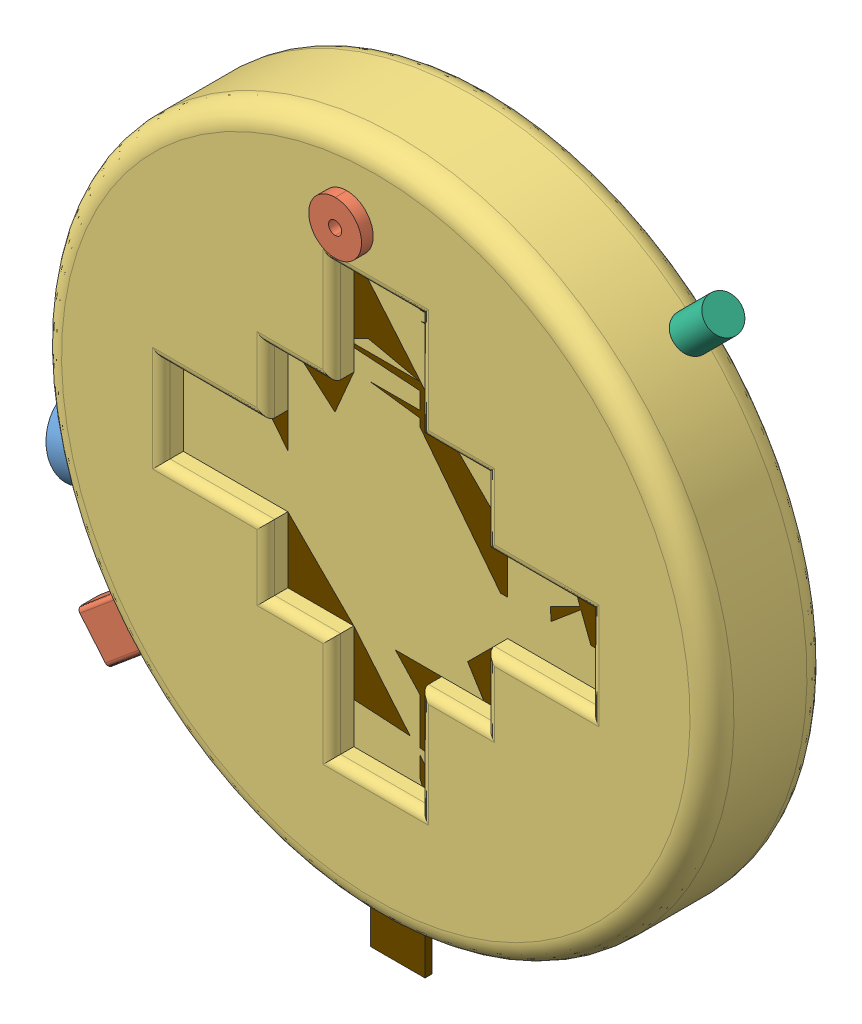
SolidWorks assembly Semafor2_s_obalem, configuration Výchozí. Lengths in mm.
Overall size (156.29 162.78 29.25).
175 component instances, 21 part files, 3 mates.
Components (placement in the parent):
- Semafor2_kompletni-1: Semafor2_kompletni [Výchozí] at origin size (154.19 160.68 28.8)
  - Semafor2-1: Semafor2 [Výchozí] at origin size (148.79 160.68 28.8)
    - Semafor2.step-1: Semafor2.step [Výchozí] at origin size (148.79 160.68 28.8)
      - LED_WS2812B_PLCC4_5.0x5.0mm_P3.2mm.step-1: LED_WS2812B_PLCC4_5.0x5.0mm_P3.2mm.step [Výchozí] at (-39.4282 65.1 1.65) x (0.5 0.866025 0) z (0 0 1) size (5.4 5 1.6)
        - SOLID.step-1: SOLID.step [Výchozí] at origin size (5.4 5 1.6)
      - Piezo.step-1: Piezo.step [Výchozí] at (-106.6 158.895 1.65) x (1 0 0) z (0 -1 0) size (12 7.6 12)
        - SOLID-0.step-1: SOLID-0.step [Výchozí] at origin size (12 7.6 12)
      - LED_WS2812B_PLCC4_5.0x5.0mm_P3.2mm.step-2: LED_WS2812B_PLCC4_5.0x5.0mm_P3.2mm.step [Výchozí] at (-30.05 100.1 1.65) x (0 1 0) z (0 0 1) size (5.4 5 1.6)
        - SOLID.step-1: SOLID.step [Výchozí] at origin size (5.4 5 1.6)
      - LED_WS2812B_PLCC4_5.0x5.0mm_P3.2mm.step-3: LED_WS2812B_PLCC4_5.0x5.0mm_P3.2mm.step [Výchozí] at (-170.05 100.1 1.65) x (0 -1 0) z (0 0 1) size (5.4 5 1.6)
        - SOLID.step-1: SOLID.step [Výchozí] at origin size (5.4 5 1.6)
      - C_0603_1608Metric.step-1: C_0603_1608Metric.step [Výchozí] at (-101.75 33.8 1.65) size (1.6 0.8 0.8)
        - SOLID-1.step-1: SOLID-1.step [Výchozí] at origin size (1.6 0.8 0.8)
      - C_0603_1608Metric.step-2: C_0603_1608Metric.step [Výchozí] at (-43.5875 65.6288 1.65) x (0.5 0.866025 0) z (0 0 1) size (1.6 0.8 0.8)
        - SOLID-1.step-1: SOLID-1.step [Výchozí] at origin size (1.6 0.8 0.8)
      - C_0603_1608Metric.step-3: C_0603_1608Metric.step [Výchozí] at (-134.4288 43.6125 1.65) x (0.866025 -0.5 0) z (0 0 1) size (1.6 0.8 0.8)
        - SOLID-1.step-1: SOLID-1.step [Výchozí] at origin size (1.6 0.8 0.8)
      - C_0603_1608Metric.step-4: C_0603_1608Metric.step [Výchozí] at (-166.15 101.75 1.65) x (0 -1 0) z (0 0 1) size (1.6 0.8 0.8)
        - SOLID-1.step-1: SOLID-1.step [Výchozí] at origin size (1.6 0.8 0.8)
      - LED_WS2812B_PLCC4_5.0x5.0mm_P3.2mm.step-4: LED_WS2812B_PLCC4_5.0x5.0mm_P3.2mm.step [Výchozí] at (-100.05 30.1 1.65) size (5.4 5 1.6)
        - SOLID.step-1: SOLID.step [Výchozí] at origin size (5.4 5 1.6)
      - C_0603_1608Metric.step-5: C_0603_1608Metric.step [Výchozí] at (-158.05 68.5 1.65) x (0.5 -0.866025 0) z (0 0 1) size (1.6 0.8 0.8)
        - SOLID-1.step-1: SOLID-1.step [Výchozí] at origin size (1.6 0.8 0.8)
      - C_0603_1608Metric.step-6: C_0603_1608Metric.step [Výchozí] at (-68.35 41.95 1.65) x (0.866025 0.5 0) z (0 0 1) size (1.6 0.8 0.8)
        - SOLID-1.step-1: SOLID-1.step [Výchozí] at origin size (1.6 0.8 0.8)
      - LED_WS2812B_PLCC4_5.0x5.0mm_P3.2mm.step-5: LED_WS2812B_PLCC4_5.0x5.0mm_P3.2mm.step [Výchozí] at (-100.05 170.1 1.65) x (-1 0 0) z (0 0 1) size (5.4 5 1.6)
        - SOLID.step-1: SOLID.step [Výchozí] at origin size (5.4 5 1.6)
      - LED_WS2812B_PLCC4_5.0x5.0mm_P3.2mm.step-6: LED_WS2812B_PLCC4_5.0x5.0mm_P3.2mm.step [Výchozí] at (-39.4282 135.1 1.65) x (-0.5 0.866025 0) z (0 0 1) size (5.4 5 1.6)
        - SOLID.step-1: SOLID.step [Výchozí] at origin size (5.4 5 1.6)
      - LED_WS2812B_PLCC4_5.0x5.0mm_P3.2mm.step-7: LED_WS2812B_PLCC4_5.0x5.0mm_P3.2mm.step [Výchozí] at (-160.6718 65.1 1.65) x (0.5 -0.866025 0) z (0 0 1) size (5.4 5 1.6)
        - SOLID.step-1: SOLID.step [Výchozí] at origin size (5.4 5 1.6)
      - LED_WS2812B_PLCC4_5.0x5.0mm_P3.2mm.step-8: LED_WS2812B_PLCC4_5.0x5.0mm_P3.2mm.step [Výchozí] at (-65.05 39.4782 1.65) x (0.866025 0.5 0) z (0 0 1) size (5.4 5 1.6)
        - SOLID.step-1: SOLID.step [Výchozí] at origin size (5.4 5 1.6)
      - C_0603_1608Metric.step-7: C_0603_1608Metric.step [Výchozí] at (-65.45 156.55 1.65) x (-0.866025 0.5 0) z (0 0 1) size (1.6 0.8 0.8)
        - SOLID-1.step-1: SOLID-1.step [Výchozí] at origin size (1.6 0.8 0.8)
      - C_0603_1608Metric.step-8: C_0603_1608Metric.step [Výchozí] at (-33.9 98.45 1.65) x (0 1 0) z (0 0 1) size (1.6 0.8 0.8)
        - SOLID-1.step-1: SOLID-1.step [Výchozí] at origin size (1.6 0.8 0.8)
      - C_0603_1608Metric.step-9: C_0603_1608Metric.step [Výchozí] at (-98.4 166.3 1.65) x (-1 0 0) z (0 0 1) size (1.6 0.8 0.8)
        - SOLID-1.step-1: SOLID-1.step [Výchozí] at origin size (1.6 0.8 0.8)
      - LED_WS2812B_PLCC4_5.0x5.0mm_P3.2mm.step-9: LED_WS2812B_PLCC4_5.0x5.0mm_P3.2mm.step [Výchozí] at (-160.6718 135.1 1.65) x (-0.5 -0.866025 0) z (0 0 1) size (5.4 5 1.6)
        - SOLID.step-1: SOLID.step [Výchozí] at origin size (5.4 5 1.6)
      - LED_WS2812B_PLCC4_5.0x5.0mm_P3.2mm.step-10: LED_WS2812B_PLCC4_5.0x5.0mm_P3.2mm.step [Výchozí] at (-65.05 160.7218 1.65) x (-0.866025 0.5 0) z (0 0 1) size (5.4 5 1.6)
        - SOLID.step-1: SOLID.step [Výchozí] at origin size (5.4 5 1.6)
      - C_0603_1608Metric.step-10: C_0603_1608Metric.step [Výchozí] at (-156.35 134.6 1.65) x (-0.5 -0.866025 0) z (0 0 1) size (1.6 0.8 0.8)
        - SOLID-1.step-1: SOLID-1.step [Výchozí] at origin size (1.6 0.8 0.8)
      - LED_WS2812B_PLCC4_5.0x5.0mm_P3.2mm.step-11: LED_WS2812B_PLCC4_5.0x5.0mm_P3.2mm.step [Výchozí] at (-135.05 160.7218 1.65) x (-0.866025 -0.5 0) z (0 0 1) size (5.4 5 1.6)
        - SOLID.step-1: SOLID.step [Výchozí] at origin size (5.4 5 1.6)
      - C_0603_1608Metric.step-11: C_0603_1608Metric.step [Výchozí] at (-131.65 158.3 1.65) x (-0.866025 -0.5 0) z (0 0 1) size (1.6 0.8 0.8)
        - SOLID-1.step-1: SOLID-1.step [Výchozí] at origin size (1.6 0.8 0.8)
      - C_0603_1608Metric.step-12: C_0603_1608Metric.step [Výchozí] at (-42.05 131.8 1.65) x (-0.5 0.866025 0) z (0 0 1) size (1.6 0.8 0.8)
        - SOLID-1.step-1: SOLID-1.step [Výchozí] at origin size (1.6 0.8 0.8)
      - LED_WS2812B_PLCC4_5.0x5.0mm_P3.2mm.step-12: LED_WS2812B_PLCC4_5.0x5.0mm_P3.2mm.step [Výchozí] at (-135.05 39.4782 1.65) x (0.866025 -0.5 0) z (0 0 1) size (5.4 5 1.6)
        - SOLID.step-1: SOLID.step [Výchozí] at origin size (5.4 5 1.6)
      - R_0603_1608Metric.step-1: R_0603_1608Metric.step [Výchozí] at (-119.75 147.925 -0.05) x (0 -1 0) z (0 0 -1) size (1.6 0.8 0.45)
        - SOLID-2.step-1: SOLID-2.step [Výchozí] at origin size (1.6 0.8 0.45)
      - R_0603_1608Metric.step-2: R_0603_1608Metric.step [Výchozí] at (-115.95 147.9 -0.05) x (0 -1 0) z (0 0 -1) size (1.6 0.8 0.45)
        - SOLID-2.step-1: SOLID-2.step [Výchozí] at origin size (1.6 0.8 0.45)
      - D_SOD-123.step-1: D_SOD-123.step [Výchozí] at (-130.0125 82.075 -0.05) x (-1 0 0) z (0 0 -1) size (3.8 1.6 1.25)
        - SOLID-3.step-1: SOLID-3.step [Výchozí] at origin size (3.8 1.6 1.25)
      - E22_900T22D.step-1: E22_900T22D.step [Výchozí] at (-60.45 137.7711 -0.05) x (-0.707107 -0.707107 0) z (0 0 -1) size (50 21 17.3)
        - SOLID-4.step-1: SOLID-4.step [Výchozí] at origin size (50 21 17.3)
      - D_SOD-123.step-2: D_SOD-123.step [Výchozí] at (-96.1 29.05 -0.05) x (0 -1 0) z (0 0 -1) size (3.8 1.6 1.25)
        - SOLID-3.step-1: SOLID-3.step [Výchozí] at origin size (3.8 1.6 1.25)
      - PinSocket_1x03_P2.54mm_Vertical.step-1: PinSocket_1x03_P2.54mm_Vertical.step [Výchozí] at (-143.675 75.375 -0.05) x (0 1 0) z (0 0 -1) size (2.54 7.62 10.1)
        - SOLID-5.step-1: SOLID-5.step [Výchozí] at origin size (2.54 7.62 10.1)
      - D_SOD-323.step-1: D_SOD-323.step [Výchozí] at (-142.6 58.8 -0.05) x (0.642788 -0.766044 0) z (0 0 -1) size (2.5 1.25 1.1)
        - SOLID-6.step-1: SOLID-6.step [Výchozí] at origin size (2.5 1.25 1.1)
      - C_0603_1608Metric.step-13: C_0603_1608Metric.step [Výchozí] at (-158.9591 131.0993 -0.05) x (-0.939693 0.34202 0) z (0 0 -1) size (1.6 0.8 0.8)
        - SOLID-1.step-1: SOLID-1.step [Výchozí] at origin size (1.6 0.8 0.8)
      - R_0603_1608Metric.step-3: R_0603_1608Metric.step [Výchozí] at (-83.3756 132.275 -0.05) x (-1 0 0) z (0 0 -1) size (1.6 0.8 0.45)
        - SOLID-2.step-1: SOLID-2.step [Výchozí] at origin size (1.6 0.8 0.45)
      - R_0603_1608Metric.step-4: R_0603_1608Metric.step [Výchozí] at (-118.05 147.9 -0.05) x (0 -1 0) z (0 0 -1) size (1.6 0.8 0.45)
        - SOLID-2.step-1: SOLID-2.step [Výchozí] at origin size (1.6 0.8 0.45)
      - R_0603_1608Metric.step-5: R_0603_1608Metric.step [Výchozí] at (-116.95 136.3 -0.05) x (0 -1 0) z (0 0 -1) size (1.6 0.8 0.45)
        - SOLID-2.step-1: SOLID-2.step [Výchozí] at origin size (1.6 0.8 0.45)
      - C_0805_2012Metric.step-1: C_0805_2012Metric.step [Výchozí] at (-152.9591 126.5493 -0.05) x (0.939693 -0.34202 0) z (0 0 -1) size (2 1.25 1.25)
        - SOLID-7.step-1: SOLID-7.step [Výchozí] at origin size (2 1.25 1.25)
      - LED_0603_1608Metric.step-1: LED_0603_1608Metric.step [Výchozí] at (-147.525 84.025 -0.05) x (-1 0 0) z (0 0 -1) size (1.6 0.8 1.1)
        - SOLID-8.step-1: SOLID-8.step [Výchozí] at origin size (1.6 0.8 1.1)
      - SOT-23.step-1: SOT-23.step [Výchozí] at (-83.3256 136.55 -0.05) x (0 1 0) z (0 0 -1) size (2.5 3 1.2)
        - SOLID-9.step-1: SOLID-9.step [Výchozí] at origin size (2.5 3 1.2)
      - SOT-23.step-2: SOT-23.step [Výchozí] at (-146.9091 122.0993 -0.05) x (0.939693 -0.34202 0) z (0 0 -1) size (2.5 3 1.2)
        - SOLID-9.step-1: SOLID-9.step [Výchozí] at origin size (2.5 3 1.2)
      - R_0603_1608Metric.step-6: R_0603_1608Metric.step [Výchozí] at (-120.725 43.975 -0.05) x (-1 0 0) z (0 0 -1) size (1.6 0.8 0.45)
        - SOLID-2.step-1: SOLID-2.step [Výchozí] at origin size (1.6 0.8 0.45)
      - C_0805_2012Metric.step-2: C_0805_2012Metric.step [Výchozí] at (-159.7591 129.0993 -0.05) x (-0.939693 0.34202 0) z (0 0 -1) size (2 1.25 1.25)
        - SOLID-7.step-1: SOLID-7.step [Výchozí] at origin size (2 1.25 1.25)
      - R_0603_1608Metric.step-7: R_0603_1608Metric.step [Výchozí] at (-120.15 136.3 -0.05) x (0 -1 0) z (0 0 -1) size (1.6 0.8 0.45)
        - SOLID-2.step-1: SOLID-2.step [Výchozí] at origin size (1.6 0.8 0.45)
      - D_SOD-323.step-2: D_SOD-323.step [Výchozí] at (-147.5 62.875 -0.05) x (-0.766044 -0.642788 0) z (0 0 -1) size (2.5 1.25 1.1)
        - SOLID-6.step-1: SOLID-6.step [Výchozí] at origin size (2.5 1.25 1.1)
      - C_0805_2012Metric.step-3: C_0805_2012Metric.step [Výchozí] at (-128.3875 78.75 -0.05) x (0 -1 0) z (0 0 -1) size (2 1.25 1.25)
        - SOLID-7.step-1: SOLID-7.step [Výchozí] at origin size (2 1.25 1.25)
      - R_0603_1608Metric.step-8: R_0603_1608Metric.step [Výchozí] at (-143.0091 117.4493 -0.05) x (0.939693 -0.34202 0) z (0 0 -1) size (1.6 0.8 0.45)
        - SOLID-2.step-1: SOLID-2.step [Výchozí] at origin size (1.6 0.8 0.45)
      - LED_0603_1608Metric.step-2: LED_0603_1608Metric.step [Výchozí] at (-109.425 43.2125 -0.05) x (0 -1 0) z (0 0 -1) size (1.6 0.8 1.1)
        - SOLID-8.step-1: SOLID-8.step [Výchozí] at origin size (1.6 0.8 1.1)
      - R_0603_1608Metric.step-9: R_0603_1608Metric.step [Výchozí] at (-135.1875 77.025 -0.05) x (0 1 0) z (0 0 -1) size (1.6 0.8 0.45)
        - SOLID-2.step-1: SOLID-2.step [Výchozí] at origin size (1.6 0.8 0.45)
      - USB_C.step-1: USB_C.step [Výchozí] at (-154.7 55.1 -0.05) x (-0.766044 -0.642788 0) z (0 0 -1) size (7.5 9 3.5)
        - SOLID-10.step-1: SOLID-10.step [Výchozí] at origin size (7.5 9 3.5)
      - Battery_pack.step-1: Battery_pack.step [Výchozí] at (-99.9 62.1 -0.05) x (-1 0 0) z (0 0 -1) size (77 21 19.5)
        - SOLID-11.step-1: SOLID-11.step [Výchozí] at origin size (77 21 19.5)
      - LED_0603_1608Metric.step-3: LED_0603_1608Metric.step [Výchozí] at (-107.575 43.225 -0.05) x (0 -1 0) z (0 0 -1) size (1.6 0.8 1.1)
        - SOLID-8.step-1: SOLID-8.step [Výchozí] at origin size (1.6 0.8 1.1)
      - R_0603_1608Metric.step-10: R_0603_1608Metric.step [Výchozí] at (-144.1125 87.05 -0.05) x (1 0 0) z (0 0 -1) size (1.6 0.8 0.45)
        - SOLID-2.step-1: SOLID-2.step [Výchozí] at origin size (1.6 0.8 0.45)
      - D_SOD-123.step-3: D_SOD-123.step [Výchozí] at (-117.975 155.17 -0.05) x (-1 0 0) z (0 0 -1) size (3.8 1.6 1.25)
        - SOLID-3.step-1: SOLID-3.step [Výchozí] at origin size (3.8 1.6 1.25)
      - R_0603_1608Metric.step-11: R_0603_1608Metric.step [Výchozí] at (-114.175 160.345 -0.05) x (0 -1 0) z (0 0 -1) size (1.6 0.8 0.45)
        - SOLID-2.step-1: SOLID-2.step [Výchozí] at origin size (1.6 0.8 0.45)
      - R_0603_1608Metric.step-12: R_0603_1608Metric.step [Výchozí] at (-150.9091 118.3743 -0.05) x (-0.34202 -0.939693 0) z (0 0 -1) size (1.6 0.8 0.45)
        - SOLID-2.step-1: SOLID-2.step [Výchozí] at origin size (1.6 0.8 0.45)
      - D_SOD-323.step-3: D_SOD-323.step [Výchozí] at (-98.4 29.65 -0.05) x (0 1 0) z (0 0 -1) size (2.5 1.25 1.1)
        - SOLID-6.step-1: SOLID-6.step [Výchozí] at origin size (2.5 1.25 1.1)
      - SOIC-14_3.9x8.7mm_P1.27mm.step-1: SOIC-14_3.9x8.7mm_P1.27mm.step [Výchozí] at (-118.5 142.1 -0.05) x (0 -1 0) z (0 0 -1) size (6 8.7 1.75)
        - SOLID-12.step-1: SOLID-12.step [Výchozí] at origin size (6 8.7 1.75)
      - C_0603_1608Metric.step-14: C_0603_1608Metric.step [Výchozí] at (-124.55 142.3493 -0.05) x (0 -1 0) z (0 0 -1) size (1.6 0.8 0.8)
        - SOLID-1.step-1: SOLID-1.step [Výchozí] at origin size (1.6 0.8 0.8)
      - R_0603_1608Metric.step-13: R_0603_1608Metric.step [Výchozí] at (-147.4841 125.4493 -0.05) x (0.939693 -0.34202 0) z (0 0 -1) size (1.6 0.8 0.45)
        - SOLID-2.step-1: SOLID-2.step [Výchozí] at origin size (1.6 0.8 0.45)
      - C_0805_2012Metric.step-4: C_0805_2012Metric.step [Výchozí] at (-126.5 142.3993 -0.05) x (0 -1 0) z (0 0 -1) size (2 1.25 1.25)
        - SOLID-7.step-1: SOLID-7.step [Výchozí] at origin size (2 1.25 1.25)
      - R_0603_1608Metric.step-14: R_0603_1608Metric.step [Výchozí] at (-139.1625 81.2 -0.05) x (0 -1 0) z (0 0 -1) size (1.6 0.8 0.45)
        - SOLID-2.step-1: SOLID-2.step [Výchozí] at origin size (1.6 0.8 0.45)
      - R_0603_1608Metric.step-15: R_0603_1608Metric.step [Výchozí] at (-132.6875 77.875 -0.05) x (1 0 0) z (0 0 -1) size (1.6 0.8 0.45)
        - SOLID-2.step-1: SOLID-2.step [Výchozí] at origin size (1.6 0.8 0.45)
      - SOT-23.step-3: SOT-23.step [Výchozí] at (-118.675 160.445 -0.05) x (-1 0 0) z (0 0 -1) size (2.5 3 1.2)
        - SOLID-9.step-1: SOLID-9.step [Výchozí] at origin size (2.5 3 1.2)
      - R_0402_1005Metric.step-1: R_0402_1005Metric.step [Výchozí] at (-150.45 61 -0.05) x (0.766044 0.642788 0) z (0 0 -1) size (1 0.5 0.35)
        - SOLID-13.step-1: SOLID-13.step [Výchozí] at origin size (1 0.5 0.35)
      - C_0805_2012Metric.step-5: C_0805_2012Metric.step [Výchozí] at (-114.675 48.525 -0.05) x (-1 0 0) z (0 0 -1) size (2 1.25 1.25)
        - SOLID-7.step-1: SOLID-7.step [Výchozí] at origin size (2 1.25 1.25)
      - R_0603_1608Metric.step-16: R_0603_1608Metric.step [Výchozí] at (-152.1341 114.7493 -0.05) x (-0.34202 -0.939693 0) z (0 0 -1) size (1.6 0.8 0.45)
        - SOLID-2.step-1: SOLID-2.step [Výchozí] at origin size (1.6 0.8 0.45)
      - C_0603_1608Metric.step-15: C_0603_1608Metric.step [Výchozí] at (-78.4756 143.175 -0.05) x (0 -1 0) z (0 0 -1) size (1.6 0.8 0.8)
        - SOLID-1.step-1: SOLID-1.step [Výchozí] at origin size (1.6 0.8 0.8)
      - C_0805_2012Metric.step-6: C_0805_2012Metric.step [Výchozí] at (-120.625 46.525 -0.05) x (-1 0 0) z (0 0 -1) size (2 1.25 1.25)
        - SOLID-7.step-1: SOLID-7.step [Výchozí] at origin size (2 1.25 1.25)
      - R_0603_1608Metric.step-17: R_0603_1608Metric.step [Výchozí] at (-115.3 136.3 -0.05) x (0 1 0) z (0 0 -1) size (1.6 0.8 0.45)
        - SOLID-2.step-1: SOLID-2.step [Výchozí] at origin size (1.6 0.8 0.45)
      - SOT-23-5.step-1: SOT-23-5.step [Výchozí] at (-135.2875 81.1 -0.05) x (-1 0 0) z (0 0 -1) size (2.8 2.9 1.55)
        - SOLID-14.step-1: SOLID-14.step [Výchozí] at origin size (2.8 2.9 1.55)
      - R_0402_1005Metric.step-2: R_0402_1005Metric.step [Výchozí] at (-148.35 58.75 -0.05) x (0.766044 0.642788 0) z (0 0 -1) size (1 0.5 0.35)
        - SOLID-13.step-1: SOLID-13.step [Výchozí] at origin size (1 0.5 0.35)
      - C_0805_2012Metric.step-7: C_0805_2012Metric.step [Výchozí] at (-136.7875 84.075 -0.05) x (1 0 0) z (0 0 -1) size (2 1.25 1.25)
        - SOLID-7.step-1: SOLID-7.step [Výchozí] at origin size (2 1.25 1.25)
      - PinHeader_1x02_P2.54mm_Vertical.step-1: PinHeader_1x02_P2.54mm_Vertical.step [Výchozí] at (-83.2244 144.25 -0.05) x (-1 0 0) z (0 0 -1) size (2.54 5.08 11.54)
        - SOLID-15.step-1: SOLID-15.step [Výchozí] at origin size (2.54 5.08 11.54)
      - D_SOD-323.step-4: D_SOD-323.step [Výchozí] at (-146.2 61.275 -0.05) x (-0.766044 -0.642788 0) z (0 0 -1) size (2.5 1.25 1.1)
        - SOLID-6.step-1: SOLID-6.step [Výchozí] at origin size (2.5 1.25 1.1)
      - LED_0603_1608Metric.step-4: LED_0603_1608Metric.step [Výchozí] at (-147.5125 87.075 -0.05) x (-1 0 0) z (0 0 -1) size (1.6 0.8 1.1)
        - SOLID-8.step-1: SOLID-8.step [Výchozí] at origin size (1.6 0.8 1.1)
      - R_0603_1608Metric.step-18: R_0603_1608Metric.step [Výchozí] at (-156.1591 128.8493 -0.05) x (0.939693 -0.34202 0) z (0 0 -1) size (1.6 0.8 0.45)
        - SOLID-2.step-1: SOLID-2.step [Výchozí] at origin size (1.6 0.8 0.45)
      - R_0603_1608Metric.step-19: R_0603_1608Metric.step [Výchozí] at (-144.15 84.05 -0.05) x (1 0 0) z (0 0 -1) size (1.6 0.8 0.45)
        - SOLID-2.step-1: SOLID-2.step [Výchozí] at origin size (1.6 0.8 0.45)
      - R_0603_1608Metric.step-20: R_0603_1608Metric.step [Výchozí] at (-110.275 40.775 -0.05) x (1 0 0) z (0 0 -1) size (1.6 0.8 0.45)
        - SOLID-2.step-1: SOLID-2.step [Výchozí] at origin size (1.6 0.8 0.45)
      - D_SOD-123.step-4: D_SOD-123.step [Výchozí] at (-144.6 55.65 -0.05) x (-0.766044 -0.642788 0) z (0 0 -1) size (3.8 1.6 1.25)
        - SOLID-3.step-1: SOLID-3.step [Výchozí] at origin size (3.8 1.6 1.25)
      - SOT-23.step-4: SOT-23.step [Výchozí] at (-143.8591 114.7993 -0.05) x (0.939693 -0.34202 0) z (0 0 -1) size (2.5 3 1.2)
        - SOLID-9.step-1: SOLID-9.step [Výchozí] at origin size (2.5 3 1.2)
      - R_0603_1608Metric.step-21: R_0603_1608Metric.step [Výchozí] at (-155.1091 131.9243 -0.05) x (-0.34202 -0.939693 0) z (0 0 -1) size (1.6 0.8 0.45)
        - SOLID-2.step-1: SOLID-2.step [Výchozí] at origin size (1.6 0.8 0.45)
      - R_0603_1608Metric.step-22: R_0603_1608Metric.step [Výchozí] at (-118.55 136.3 -0.05) x (0 -1 0) z (0 0 -1) size (1.6 0.8 0.45)
        - SOLID-2.step-1: SOLID-2.step [Výchozí] at origin size (1.6 0.8 0.45)
      - R_0603_1608Metric.step-23: R_0603_1608Metric.step [Výchozí] at (-121.75 136.2993 -0.05) x (0 -1 0) z (0 0 -1) size (1.6 0.8 0.45)
        - SOLID-2.step-1: SOLID-2.step [Výchozí] at origin size (1.6 0.8 0.45)
      - D_SOD-123.step-5: D_SOD-123.step [Výchozí] at (-74.5506 143.175 -0.05) x (0 -1 0) z (0 0 -1) size (3.8 1.6 1.25)
        - SOLID-3.step-1: SOLID-3.step [Výchozí] at origin size (3.8 1.6 1.25)
      - Semafor PCB.step-1: Semafor PCB.step [Výchozí] at origin size (148.79 160.68 1.6)
  - Button-2: Button [Výchozí] at (-163.9042 80.1546 -4.5) x (-0.296139 0.955145 0) z (0 0 1) size (17 22 17)
  - USB_cable-1: USB_cable [Výchozí] at (-163.701 47.5472 -4.8) x (0.766044 0.642788 0) z (0 0 1) size (20 11 6)
- Obal-1: Obal [Výchozí] at (-100 99.9315 0) x (0 1 0) z (0 0 -1) size (153 153 26.6)
Mates (geometry in assembly coordinates):
- Soustředná1: concentric: circle of Semafor2_kompletni-1/Semafor2-1/Semafor2.step-1/Semafor PCB.step-1; circle of Obal-1
- Sjednocená1: coincident: plane of Semafor2_kompletni-1/Semafor2-1/Semafor2.step-1/Semafor PCB.step-1 through (-100.0019 93.8452 1.6) normal (0 0 1); plane of Obal-1 through (-100 99.9315 1.6) normal (0 0 1)
- Rovnoběžná1: parallel anti-aligned: plane of Semafor2_kompletni-1/Semafor2-1/Semafor2.step-1/Semafor PCB.step-1 through (-93.8 13.65 0) normal (0 -1 0); plane of Obal-1 through (-90 51.1315 1.6) normal (0 1 0)
